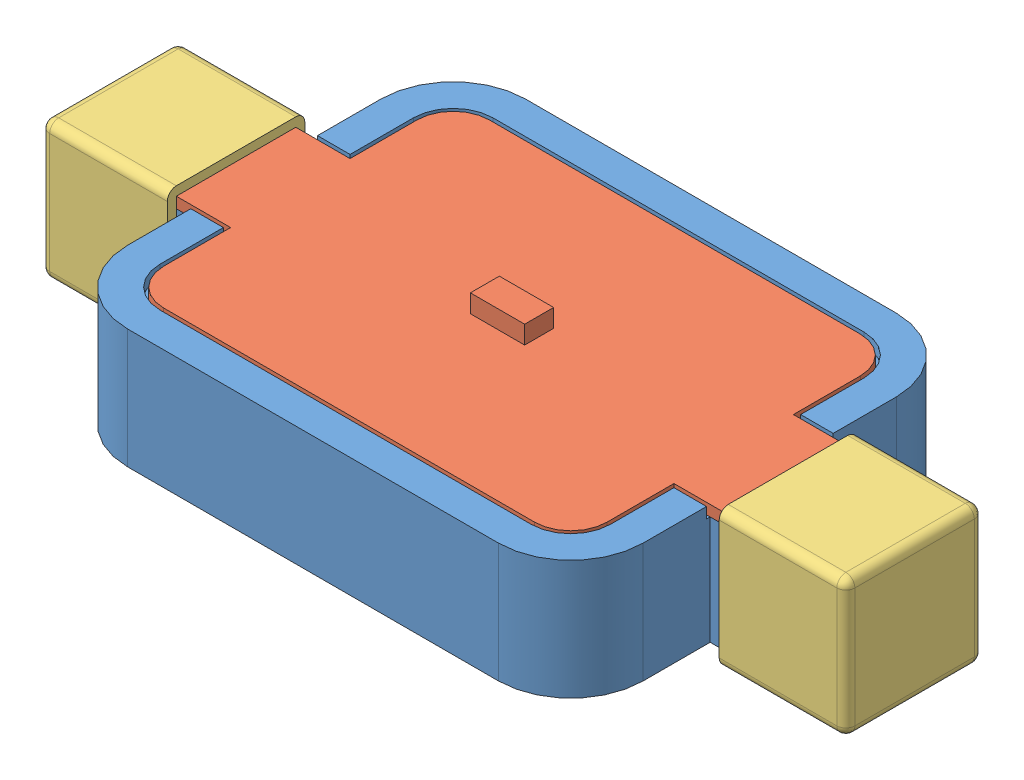
SolidWorks assembly ComponentAssemblyBuild, configuration Default. Lengths in mm.
Overall size (44.5 8.1 22).
4 component instances, 3 part files, 7 mates.
Components (placement in the parent):
- ABSpart-1: ABSpart [Default] at (15.1077 0 27.3187) size (43.5 6.6 22)
- PCB-1: PCB [Default] at (15.1077 0 27.3187) size (43.5 1.6 18)
- Cap2-1: Cap2 [Default] at (-0.1423 3.3 27.3187) x (0 1 0) z (0 0 1) size (7.6 7 7.6)
- Cap2-2: Cap2 [Default] at (30.3577 3.3 27.3187) x (0 -1 0) z (0 0 1) size (7.6 7 7.6)
Mates (geometry in assembly coordinates):
- Coincident1: coincident aligned: plane of ABSpart-1 through (15.1077 0 27.3187) normal (0 1 0); plane of assembly through (0 0 0) normal (0 1 0)
- Coincident2: coincident anti-aligned: plane of ABSpart-1 through (-6.6423 6.6 30.6187) normal (-1 0 0); plane of Cap2-1 through (-6.6423 3.3 27.3187) normal (1 0 0)
- Coincident3: coincident anti-aligned: plane of ABSpart-1 through (36.8577 6.6 30.6187) normal (1 0 0); plane of Cap2-2 through (36.8577 3.3 27.3187) normal (-1 0 0)
- Coincident4: coincident anti-aligned: plane of ABSpart-1 through (4.8577 0 20.3187) normal (0 -1 0); plane of Cap2-2 through (36.8577 0 24.0187) normal (0 1 0)
- Coincident5: coincident anti-aligned: plane of ABSpart-1 through (29.3577 6.6 24.0187) normal (0 0 -1); plane of Cap2-2 through (36.8577 6.6 24.0187) normal (0 0 1)
- Coincident6: coincident anti-aligned: plane of ABSpart-1 through (4.8577 0 20.3187) normal (0 -1 0); plane of Cap2-1 through (-6.6423 0 30.6187) normal (0 1 0)
- Coincident7: coincident anti-aligned: plane of ABSpart-1 through (-6.6423 6.6 24.0187) normal (0 0 -1); plane of Cap2-1 through (-6.6423 0 24.0187) normal (0 0 1)
